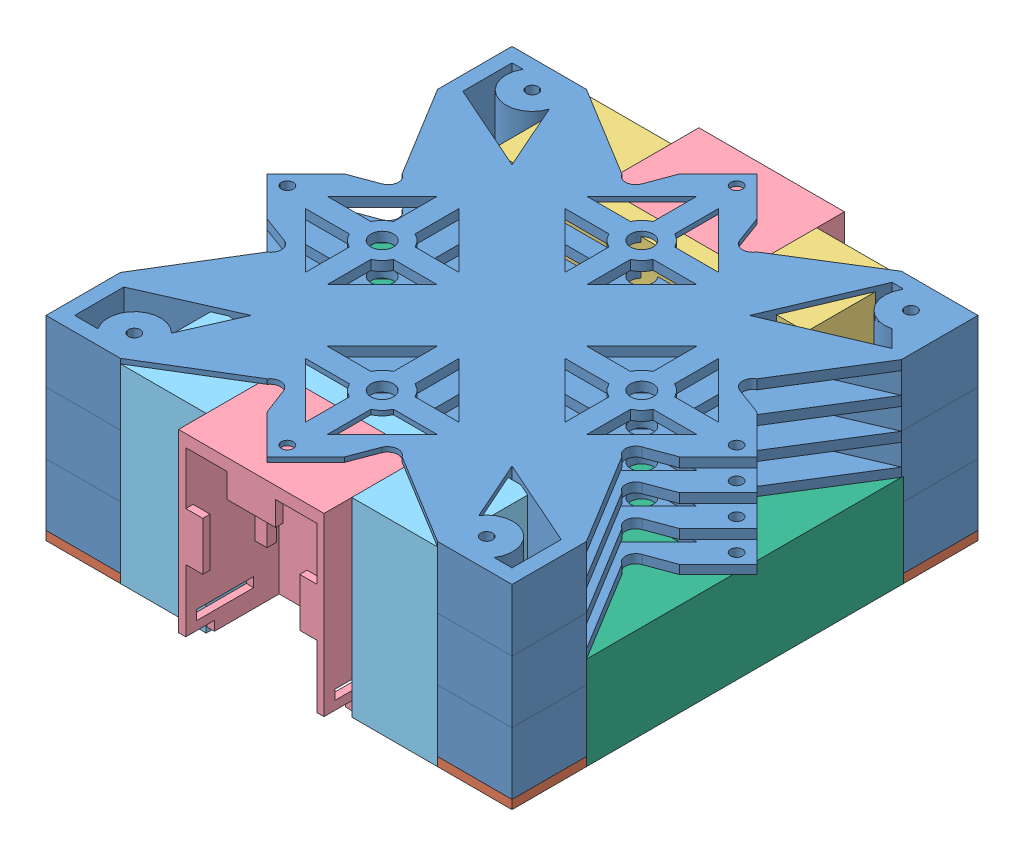
SolidWorks assembly BottomStart, configuration Default. Lengths in mm.
Overall size (102.59 40.85 109.22).
12 component instances, 9 part files, 41 mates.
Components (placement in the parent):
- 3dppart2-1: 3dppart2 [Default] at (-239.2395 19.4977 248.322) size (102.59 13 102.59)
- 3dppart2-2: 3dppart2 [Default] at (-239.2395 32.4977 248.322) size (102.59 13 102.59)
- 3dppart2-3: 3dppart2 [Default] at (-239.2395 45.4977 248.322) size (102.59 13 102.59)
- 3dprintpart-1: 3dprintpart [Default] at (-239.2395 6.6477 248.322) size (97.6 1.85 97.6)
- Part2^BottomStart-1: Part2^BottomStart [Default] at (-239.2395 47.4977 248.322) x (1 0 0) z (0 1 0) (virtual)
- Part3^BottomStart-1: Part3^BottomStart [Default] at (-239.2395 47.4977 248.322) x (1 0 0) z (0 1 0) (virtual)
- Part4^BottomStart-1: Part4^BottomStart [Default] at (-239.2395 47.4977 248.322) x (1 0 0) z (0 1 0) (virtual)
- BottomAntennaAttach1-1: BottomAntennaAttach1 [Default] at (-190.6614 26.5727 170.722) x (-1 0 0) z (0 0 -1) size (65.99 39.85 20)
- Base-1: Base [Default] at (-190.6614 21.0977 163.964) x (1 0 0) z (0 0 -1) size (30.48 38.86 20.83)
- Base-2: Base [Default] at (-190.4395 21.0977 235.08) x (-1 0 0) z (0 0 1) size (30.48 38.86 20.83)
- BottomAntennaAttach2-2: BottomAntennaAttach2 [Default] at (-190.4395 26.5727 228.322) size (66.44 39.85 20)
- GPSHolder-1: GPSHolder [Default] at (-190.4395 26.1477 199.522) x (-1 0 0) z (0 0 1) size (97.6 19.5 66.44)
Mates (geometry in assembly coordinates):
- Coincident1: coincident aligned: plane of 3dppart2-2 through (-239.2395 32.4977 248.322) normal (0 0 1); plane of 3dppart2-3 through (-239.2395 45.4977 248.322) normal (0 0 1)
- Coincident2: coincident aligned: plane of 3dppart2-1 through (-239.2395 19.4977 248.322) normal (0 0 1); plane of 3dppart2-2 through (-239.2395 32.4977 248.322) normal (0 0 1)
- Coincident3: coincident anti-aligned: plane of 3dppart2-2 through (-239.2395 34.4977 248.322) normal (0 1 0); plane of 3dppart2-3 through (-239.2395 34.4977 248.322) normal (0 -1 0)
- Coincident4: coincident anti-aligned: plane of 3dppart2-1 through (-239.2395 21.4977 248.322) normal (0 1 0); plane of 3dppart2-2 through (-239.2395 21.4977 248.322) normal (0 -1 0)
- Coincident5: coincident aligned: plane of 3dppart2-2 through (-141.6395 32.4977 248.322) normal (1 0 0); plane of 3dppart2-3 through (-141.6395 45.4977 248.322) normal (1 0 0)
- Coincident6: coincident aligned: plane of 3dppart2-1 through (-141.6395 19.4977 248.322) normal (1 0 0); plane of 3dppart2-2 through (-141.6395 32.4977 248.322) normal (1 0 0)
- Coincident7: coincident anti-aligned: plane of 3dppart2-1 through (-239.2395 8.4977 248.322) normal (0 -1 0); plane of 3dprintpart-1 through (-239.2395 8.4977 248.322) normal (0 1 0)
- Coincident8: coincident aligned: plane of 3dppart2-1 through (-239.2395 19.4977 248.322) normal (0 0 1); plane of 3dprintpart-1 through (-239.2395 8.4977 248.322) normal (0 0 1)
- Coincident9: coincident aligned: plane of 3dppart2-1 through (-141.6395 19.4977 248.322) normal (1 0 0); plane of 3dprintpart-1 through (-141.6395 8.4977 248.322) normal (1 0 0)
- InPlace1: in place: plane of 3dppart2-3 through (-239.2395 47.4977 248.322) normal (0 1 0); plane of ? through (0 47.4977 0) normal (0 1 0); moOrthogonalPlaneRef_w of 3dppart2-3 through (-239.2395 47.4977 248.322) normal (0 1 0); plane of ? through (0 47.4977 0) normal (0 0 -1); plane of 3dppart2-3 through (-239.2395 47.4977 248.322) normal (0 1 0); line of ? through (-55 0 47.4977) axis (0 1 0); plane of 3dppart2-3 through (-239.2395 47.4977 248.322) normal (0 1 0); unknown of ?
- Coincident10: coincident aligned: plane of 3dppart2-3; plane of Part2^BottomStart-1
- Coincident11: coincident aligned: moOrthogonalPlaneRef_w of 3dppart2-3 through (-239.2395 47.4977 248.322) normal (0 0 -1); plane of Part2^BottomStart-1 through (-239.2395 47.4977 248.322) normal (0 0 -1)
- Coincident12: coincident anti-aligned: moOrthogonalPlaneRef_w of 3dppart2-3 through (-239.2395 47.4977 248.322) normal (-1 0 0); plane of Part2^BottomStart-1
- InPlace2: in place: plane of 3dppart2-3 through (-239.2395 47.4977 248.322) normal (0 1 0); plane of ? through (0 47.4977 0) normal (0 1 0); plane of 3dppart2-3 through (-239.2395 47.4977 248.322) normal (0 1 0); plane of ? through (0 47.4977 0) normal (0 0 -1); plane of 3dppart2-3 through (-239.2395 47.4977 248.322) normal (0 1 0); line of ? through (-55 0 47.4977) axis (0 1 0); plane of 3dppart2-3 through (-239.2395 47.4977 248.322) normal (0 1 0); unknown of ?
- Coincident13: coincident aligned: plane of 3dppart2-3; plane of Part3^BottomStart-1
- Coincident14: coincident aligned: moOrthogonalPlaneRef_w of 3dppart2-3 through (-239.2395 47.4977 248.322) normal (0 0 -1); plane of Part3^BottomStart-1 through (-239.2395 47.4977 248.322) normal (0 0 -1)
- Coincident15: coincident anti-aligned: moOrthogonalPlaneRef_w of 3dppart2-3 through (-239.2395 47.4977 248.322) normal (-1 0 0); plane of Part3^BottomStart-1
- InPlace3: in place: plane of 3dppart2-3 through (-239.2395 47.4977 248.322) normal (0 1 0); plane of ? through (0 47.4977 0) normal (0 1 0); plane of 3dppart2-3 through (-239.2395 47.4977 248.322) normal (0 1 0); plane of ? through (0 47.4977 0) normal (0 0 -1); plane of 3dppart2-3 through (-239.2395 47.4977 248.322) normal (0 1 0); line of ? through (-55 0 47.4977) axis (0 1 0); plane of 3dppart2-3 through (-239.2395 47.4977 248.322) normal (0 1 0); unknown of ?
- Coincident16: coincident aligned: plane of 3dppart2-3; plane of Part4^BottomStart-1
- Coincident17: coincident aligned: moOrthogonalPlaneRef_w of 3dppart2-3 through (-239.2395 47.4977 248.322) normal (0 0 -1); plane of Part4^BottomStart-1 through (-239.2395 47.4977 248.322) normal (0 0 -1)
- Coincident18: coincident anti-aligned: moOrthogonalPlaneRef_w of 3dppart2-3 through (-239.2395 47.4977 248.322) normal (-1 0 0); plane of Part4^BottomStart-1
- Coincident10: coincident anti-aligned: plane of 3dppart2-1 through (-157.6645 45.4977 170.722) normal (-1 0 0); plane of BottomAntennaAttach1-1 through (-157.6645 46.4977 150.722) normal (1 0 0)
- Coincident11: coincident anti-aligned: plane of 3dppart2-1 through (-223.6583 45.4977 170.722) normal (1 0 0); plane of BottomAntennaAttach1-1 through (-223.6583 46.4977 150.722) normal (-1 0 0)
- Coincident12: coincident anti-aligned: plane of 3dppart2-3 through (0 46.4977 0) normal (0 -1 0); plane of BottomAntennaAttach1-1 through (-223.6583 46.4977 150.722) normal (0 1 0)
- Coincident18: coincident anti-aligned: plane of 3dppart2-2 through (-157.2208 45.4977 228.322) normal (-1 0 0); plane of BottomAntennaAttach2-2 through (-157.2208 46.4977 248.322) normal (1 0 0)
- Coincident21: coincident anti-aligned: plane of 3dppart2-2 through (-223.6583 45.4977 228.322) normal (1 0 0); plane of BottomAntennaAttach2-2 through (-223.6583 46.4977 248.322) normal (-1 0 0)
- Coincident22: coincident anti-aligned: plane of 3dppart2-3 through (0 46.4977 0) normal (0 -1 0); plane of BottomAntennaAttach2-2 through (-157.2208 46.4977 248.322) normal (0 1 0)
- Coincident23: coincident anti-aligned: plane of 3dppart2-2 through (0 0 228.322) normal (0 0 1); plane of BottomAntennaAttach2-2 through (-190.4395 26.5727 228.322) normal (0 0 -1)
- Coincident24: coincident anti-aligned: plane of Base-2 through (-205.6795 46.4977 233.302) normal (-1 0 0); plane of BottomAntennaAttach2-2 through (-205.6795 46.4977 233.302) normal (1 0 0)
- Coincident25: coincident anti-aligned: plane of 3dppart2-3 through (0 46.4977 0) normal (0 -1 0); plane of Base-2 through (-205.6795 46.4977 233.302) normal (0 1 0)
- Coincident26: coincident anti-aligned: plane of Base-2 through (-175.1995 46.4977 233.302) normal (1 0 0); plane of BottomAntennaAttach2-2 through (-175.1995 46.4977 233.302) normal (-1 0 0)
- Coincident27: coincident anti-aligned: plane of Base-2 through (-190.4395 21.0977 233.302) normal (0 0 -1); plane of BottomAntennaAttach2-2 through (-190.4395 26.5727 233.302) normal (0 0 1)
- Coincident28: coincident anti-aligned: plane of BottomAntennaAttach1-1 through (-205.9014 46.4977 165.742) normal (1 0 0); plane of Base-1 through (-205.9014 46.4977 165.742) normal (-1 0 0)
- Coincident29: coincident anti-aligned: plane of BottomAntennaAttach1-1 through (-190.6614 26.5727 165.742) normal (0 0 -1); plane of Base-1 through (-190.6614 21.0977 165.742) normal (0 0 1)
- Coincident30: coincident anti-aligned: plane of BottomAntennaAttach1-1 through (-175.4214 46.4977 165.742) normal (-1 0 0); plane of Base-1 through (-175.4214 46.4977 165.742) normal (1 0 0)
- Coincident31: coincident anti-aligned: plane of 3dppart2-3 through (0 46.4977 0) normal (0 -1 0); plane of Base-1 through (-175.4214 46.4977 165.742) normal (0 1 0)
- Lock1: lock: unknown of 3dprintpart-1; unknown of BottomAntennaAttach1-1
- Lock2: lock: unknown of 3dprintpart-1; unknown of BottomAntennaAttach2-2
- Coincident32: coincident anti-aligned: plane of 3dppart2-2 through (0 26.1477 0) normal (0 -1 0); plane of GPSHolder-1 through (-190.4395 26.1477 199.522) normal (0 1 0)
- Coincident33: coincident aligned: plane of 3dppart2-1 through (-239.2395 19.4977 248.322) normal (-1 0 0); plane of GPSHolder-1 through (-239.2395 20.1477 166.3033) normal (-1 0 0)
- Coincident34: coincident anti-aligned: plane of BottomAntennaAttach2-2 through (0 26.1477 232.7408) normal (0 0 -1); plane of GPSHolder-1 through (-239.2395 20.1477 232.7408) normal (0 0 1)
